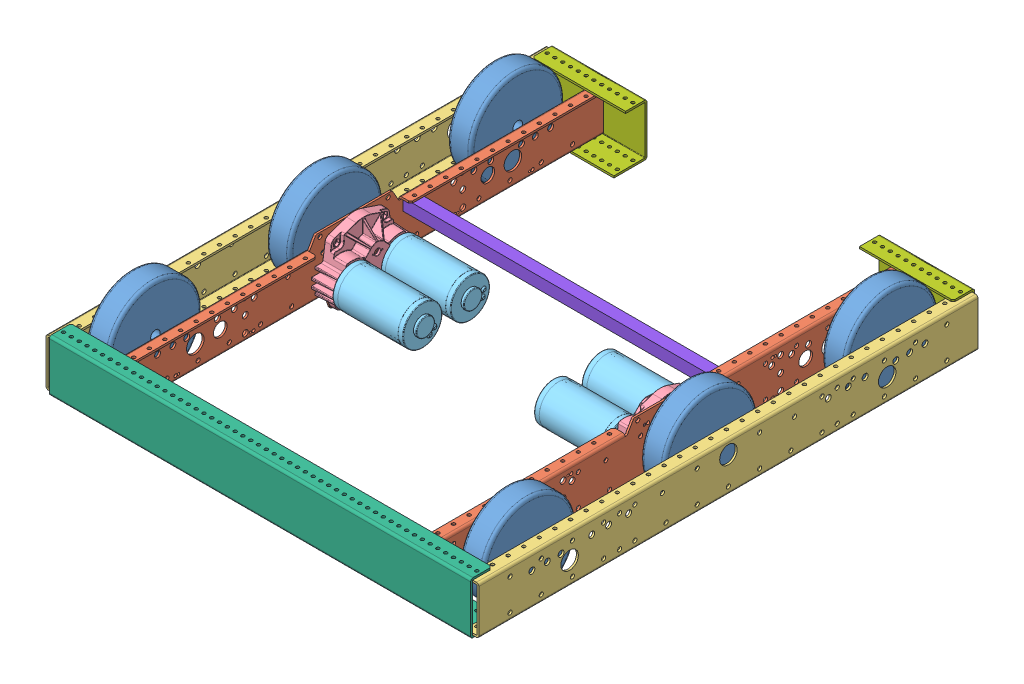
SolidWorks assembly Drive train Assem V2.0, configuration Default. Lengths in mm.
Overall size (704.85 156.21 820.67).
19 component instances, 8 part files, 27 mates.
Components (placement in the parent):
- Wheel_Six_Inch-1: Wheel_Six_Inch [Default] at (-2.6035 -76.2 42.6501) size (38.1 152.4 152.4)
- am_3922 AM14U4 Inside Plate-2: am_3922 AM14U4 Inside Plate [Default] at (-28.0035 -58.928 449.0501) x (0 0 -1) z (0 1 0) size (812.8 38.1 116.33)
- am_3921 AM14U4 Outside Plate-1: am_3921 AM14U4 Outside Plate [Default] at (60.8965 -58.928 -363.7499) x (0 0 1) z (0 1 0) size (812.8 22.23 77.72)
- Wheel_Six_Inch-2: Wheel_Six_Inch [Default] at (-2.6035 -79.756 337.7004) size (38.1 152.4 152.4)
- Wheel_Six_Inch-3: Wheel_Six_Inch [Default] at (-2.6035 -79.756 -252.4003) size (38.1 152.4 152.4)
- TM_Housing-1: TM_Housing [Default] at (-66.9925 -76.1936 42.6501) x (0 0 1) z (1 0 0) size (139.9 118.55 41.53)
- CIM_Motor-1: CIM_Motor [Default] at (-86.0425 -213.6597 116.9451) x (0 0 -1) z (1 0 0) size (64.01 64.01 154.94)
- CIM_Motor-2: CIM_Motor [Default] at (-86.0425 -214.0264 -30.4976) x (0 0.579915 -0.814677) z (1 0 0) size (64.01 64.01 154.94)
- Wheel_Six_Inch-10: Wheel_Six_Inch [Default] at (-574.1035 -76.2 42.6501) x (-1 0 0) z (0 0 -1) size (38.1 152.4 152.4)
- am_3922 AM14U4 Inside Plate-5: am_3922 AM14U4 Inside Plate [Default] at (-548.7035 -58.928 -363.7499) x (0 0 1) z (0 1 0) size (812.8 38.1 116.33)
- am_3921 AM14U4 Outside Plate-4: am_3921 AM14U4 Outside Plate [MirrorDefault] at (-637.6035 -58.928 -363.7499) x (0 0 1) z (0 -1 0) size (812.8 22.23 77.72)
- Wheel_Six_Inch-11: Wheel_Six_Inch [Default] at (-574.1035 -79.756 337.7004) x (-1 0 0) z (0 0 -1) size (38.1 152.4 152.4)
- Wheel_Six_Inch-12: Wheel_Six_Inch [Default] at (-574.1035 -79.756 -252.4003) x (-1 0 0) z (0 0 -1) size (38.1 152.4 152.4)
- TM_Housing-3: TM_Housing [Default] at (-509.7145 -76.1936 42.6501) x (0 0 -1) z (-1 0 0) size (139.9 118.55 41.53)
- CIM_Motor-5: CIM_Motor [Default] at (-490.6645 4.9327 116.9451) x (0 0 -1) z (-1 0 0) size (64.01 64.01 154.94)
- CIM_Motor-6: CIM_Motor [Default] at (-490.6645 -35.9443 96.2675) x (0 0.579915 -0.814677) z (-1 0 0) size (64.01 64.01 154.94)
- am_3920 AM14U4 End Plate Long-1: am_3920 AM14U4 End Plate Long [Default] at (-732.8535 -54.483 452.9871) x (1 0 0) z (0 1 0) size (685.8 53.98 84.58)
- am_3920 AM14U4 End Plate Long Cut-1: am_3920 AM14U4 End Plate Long Cut [Default] at (156.1465 -54.483 -367.6869) x (-1 0 0) z (0 1 0) size (685.8 53.98 84.58)
- Rod(20)-1: Rod(20) [Default] at (-31.1785 -67.691 -46.2486) x (0 0 -1) z (1 0 0) size (19.05 19.05 514.35)
Mates (geometry in assembly coordinates):
- Coincident1: coincident aligned: plane of Wheel_Six_Inch-1 through (-2.6035 0 42.6501) normal (0 1 0); plane of assembly through (0 0 0) normal (0 1 0)
- Concentric1: concentric aligned: cylinder of Wheel_Six_Inch-1 through (35.4965 -76.2 42.6501) axis (-1 0 0) radius 7.9375; cylinder of am_3922 AM14U4 Inside Plate-2 through (-28.0035 -76.2 42.6501) axis (-1 0 0) radius 14.2875
- Concentric2: concentric anti-aligned: cylinder of Wheel_Six_Inch-1 through (35.4965 -76.2 42.6501) axis (-1 0 0) radius 7.9375; cylinder of am_3921 AM14U4 Outside Plate-1 through (60.8965 -76.2 42.6501) axis (1 0 0) radius 14.2875
- Parallel3: parallel anti-aligned: plane of am_3922 AM14U4 Inside Plate-2 through (-28.0035 -132.715 -363.7499) normal (0 -1 0); plane of assembly through (0 0 0) normal (0 1 0)
- Parallel4: parallel anti-aligned: plane of am_3922 AM14U4 Inside Plate-2 through (-28.0035 -128.778 449.0501) normal (1 0 0); plane of am_3921 AM14U4 Outside Plate-1 through (60.8965 -128.778 -363.7499) normal (-1 0 0)
- Width1: width anti-aligned: plane of Wheel_Six_Inch-1 through (-2.6035 -76.2 42.6501) normal (-1 0 0); plane of am_3922 AM14U4 Inside Plate-2 through (35.4965 -76.2 42.6501) normal (1 0 0); plane of Wheel_Six_Inch-1 through (-28.0035 -128.778 449.0501) normal (1 0 0); plane of am_3921 AM14U4 Outside Plate-1 through (60.8965 -128.778 -363.7499) normal (-1 0 0)
- Coincident6: coincident aligned: plane of Wheel_Six_Inch-1 through (35.4965 -76.2 42.6501) normal (1 0 0); plane of Wheel_Six_Inch-2 through (35.4965 -79.756 337.7004) normal (1 0 0)
- Coincident7: coincident aligned: plane of Wheel_Six_Inch-1 through (35.4965 -76.2 42.6501) normal (1 0 0); plane of Wheel_Six_Inch-3 through (35.4965 -79.756 -252.4003) normal (1 0 0)
- Concentric5: concentric aligned: cylinder of am_3922 AM14U4 Inside Plate-2 through (-8.9535 -79.756 337.7004) axis (-1 0 0) radius 4.826; cylinder of Wheel_Six_Inch-2 through (35.4965 -79.756 337.7004) axis (-1 0 0) radius 7.9375
- Concentric6: concentric aligned: cylinder of am_3922 AM14U4 Inside Plate-2 through (-8.9535 -79.756 -252.4003) axis (-1 0 0) radius 4.826; cylinder of Wheel_Six_Inch-3 through (35.4965 -79.756 -252.4003) axis (-1 0 0) radius 7.9375
- Coincident13: coincident anti-aligned: plane of am_3922 AM14U4 Inside Plate-2 through (-31.1785 -128.778 449.0501) normal (-1 0 0); plane of TM_Housing-1 through (-31.1785 -76.1936 42.6501) normal (1 0 0)
- Concentric8: concentric aligned: cylinder of am_3922 AM14U4 Inside Plate-2 through (-47.0535 -146.7815 10.9001) axis (1 0 0) radius 2.5527; cone of TM_Housing-1 through (-36.5302 -146.7815 10.9001) axis (1 0 0)
- Concentric9: concentric aligned: cylinder of am_3922 AM14U4 Inside Plate-2 through (-47.0535 -146.7815 74.4001) axis (1 0 0) radius 2.5527; cone of TM_Housing-1 through (-36.5302 -146.7815 74.4001) axis (1 0 0)
- Concentric10: concentric anti-aligned: cylinder of TM_Housing-1 through (-31.1785 -104.3635 81.3851) axis (1 0 0) radius 10.414; cylinder of CIM_Motor-1 through (-62.9285 -104.3635 81.3851) axis (-1 0 0) radius 9.525
- Coincident14: coincident anti-aligned: plane of TM_Housing-1 through (-66.9925 -76.1936 42.6501) normal (-1 0 0); plane of CIM_Motor-1 through (-66.9925 -104.3635 81.3851) normal (1 0 0)
- Concentric11: concentric anti-aligned: cylinder of CIM_Motor-2 through (-62.9285 -104.3635 3.9151) axis (-1 0 0) radius 9.525; cylinder of TM_Housing-1 through (-31.1785 -104.3635 3.9151) axis (1 0 0) radius 10.414
- Coincident15: coincident anti-aligned: plane of TM_Housing-1 through (-66.9925 -76.1936 42.6501) normal (-1 0 0); plane of CIM_Motor-2 through (-66.9925 -104.3635 3.9151) normal (1 0 0)
- Coincident16: coincident aligned: plane of am_3922 AM14U4 Inside Plate-2 through (-28.0035 -132.715 -363.7499) normal (0 -1 0); plane of am_3921 AM14U4 Outside Plate-1 through (60.8965 -132.715 449.0501) normal (0 -1 0)
- Coincident17: coincident anti-aligned: plane of am_3922 AM14U4 Inside Plate-2 through (-28.0035 -132.715 -363.7499) normal (0 -1 0); plane of am_3920 AM14U4 End Plate Long-1 through (54.5465 -132.715 399.0121) normal (0 1 0)
- Concentric12: concentric aligned: cylinder of am_3921 AM14U4 Outside Plate-1 through (48.1965 -54.991 410.9501) axis (0 -1 0) radius 2.667; cylinder of am_3920 AM14U4 End Plate Long-1 through (48.1965 -130.81 410.9501) axis (0 -1 0) radius 2.667
- Concentric13: concentric anti-aligned: cylinder of am_3921 AM14U4 Outside Plate-1 through (48.1965 -54.991 436.3501) axis (0 -1 0) radius 2.667; cylinder of am_3920 AM14U4 End Plate Long-1 through (48.1965 -135.89 436.3501) axis (0 1 0) radius 2.667
- Concentric14: concentric aligned: cylinder of am_3922 AM14U4 Inside Plate-2 through (-15.3035 -54.991 410.9501) axis (0 -1 0) radius 2.667; cylinder of am_3920 AM14U4 End Plate Long-1 through (-15.3035 -130.81 410.9501) axis (0 -1 0) radius 2.667
- Coincident18: coincident anti-aligned: plane of am_3922 AM14U4 Inside Plate-2 through (-28.0035 -132.715 -363.7499) normal (0 -1 0); plane of am_3920 AM14U4 End Plate Long Cut-1 through (-631.2535 -132.715 -313.7119) normal (0 1 0)
- Concentric15: concentric anti-aligned: circle of am_3922 AM14U4 Inside Plate-2; circle of am_3920 AM14U4 End Plate Long Cut-1
- Concentric16: concentric aligned: cylinder of am_3921 AM14U4 Outside Plate-1 through (48.1965 -54.991 -325.6499) axis (0 -1 0) radius 2.667; cylinder of am_3920 AM14U4 End Plate Long Cut-1 through (48.1965 -130.81 -325.6499) axis (0 -1 0) radius 2.667
- Coincident19: coincident anti-aligned: plane of am_3922 AM14U4 Inside Plate-2 through (-31.1785 -58.166 -363.7499) normal (0 -1 0); plane of Rod(20)-1 through (-545.5285 -58.166 -36.7236) normal (0 1 0)
- Coincident21: coincident anti-aligned: plane of am_3922 AM14U4 Inside Plate-5 through (-545.5285 -128.778 -363.7499) normal (1 0 0); plane of Rod(20)-1 through (-545.5285 -67.691 -46.2486) normal (-1 0 0)
